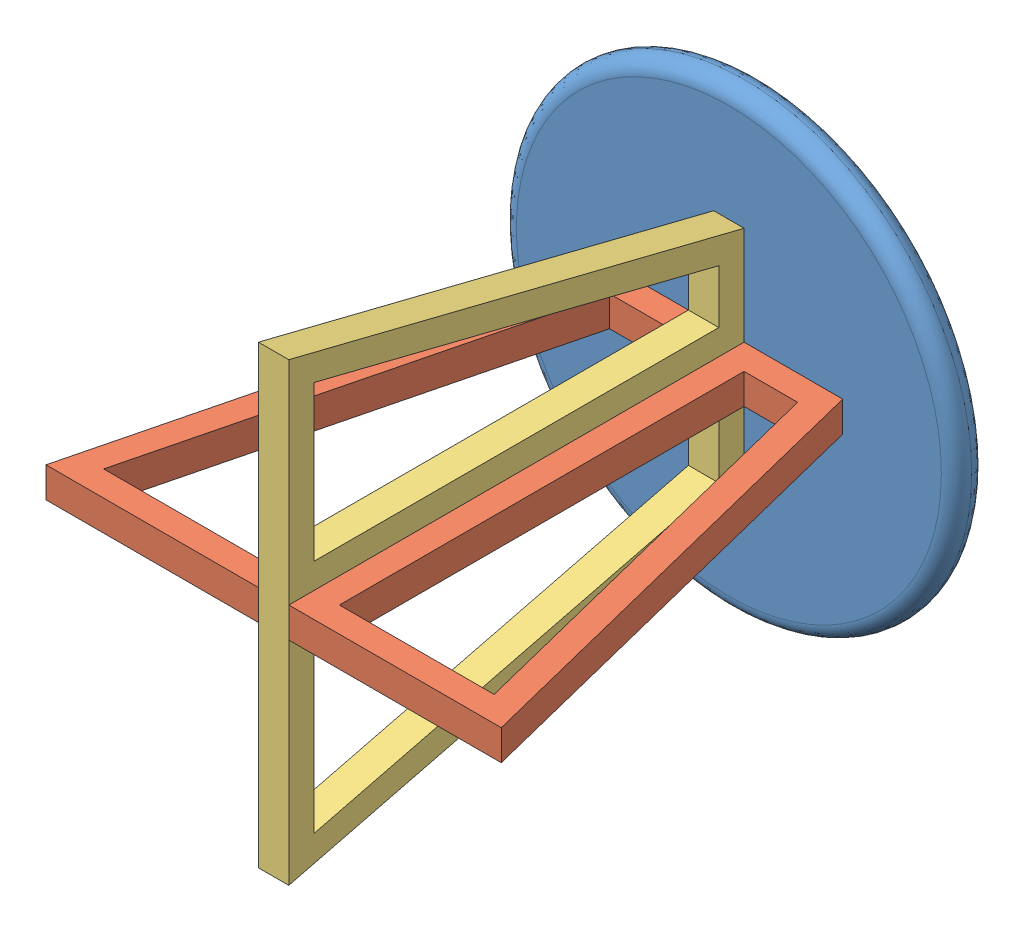
SolidWorks assembly Assem2, configuration Default. Lengths in mm.
Overall size (90 90 96).
3 component instances, 3 part files, 6 mates.
Components (placement in the parent):
- Circular_Tabletop-1: Circular_Tabletop [Default] at (12.3986 22.5692 94.2935) size (90 90 6)
- V_Leg_Left-1: V_Leg_Left [Default] at (12.3986 19.5692 200.1589) x (1 0 0) z (0 1 0) size (90 96 6)
- V_Leg_Right-1: V_Leg_Right [Default] at (15.3986 22.5692 205.9275) x (0 1 0) z (-1 0 0) size (90 96 6)
Mates (geometry in assembly coordinates):
- Coincident2: coincident: plane of Circular_Tabletop-1 through (12.3986 22.5692 100.2935) normal (0 0 1); plane of V_Leg_Left-1 through (5.1486 25.5354 100.2935) normal (0 0 -1)
- Coincident3: coincident: plane of Circular_Tabletop-1 through (12.3986 22.5692 100.2935) normal (0 0 1); plane of V_Leg_Right-1 through (9.3801 25.5692 100.2935) normal (0 0 -1)
- Coincident4: coincident: line of Circular_Tabletop-1 through (9.3986 7.3192 94.2935) axis (1 0 0); line of V_Leg_Right-1 through (9.3801 7.3192 94.2935) axis (1 0 0)
- Coincident5: coincident: line of Circular_Tabletop-1 through (-2.8514 25.5692 94.2935) axis (0 -1 0); line of V_Leg_Left-1 through (-2.8514 25.5354 94.2935) axis (0 -1 0)
- Coincident6: coincident anti-aligned: line of Circular_Tabletop-1 through (19.6486 19.5692 94.2935) axis (1 0 0); line of V_Leg_Left-1 through (27.6486 19.5692 94.2935) axis (-1 0 0)
- Coincident7: coincident anti-aligned: line of Circular_Tabletop-1 through (15.3986 29.8192 94.2935) axis (0 1 0); line of V_Leg_Right-1 through (15.3986 37.8192 94.2935) axis (0 -1 0)
